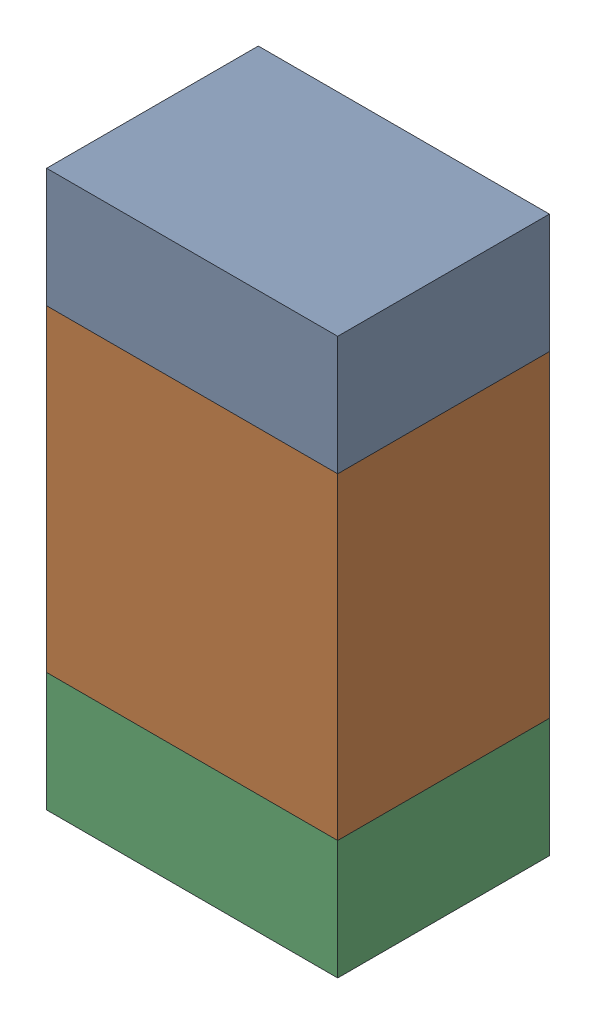
SolidWorks assembly R111_2PCB, configuration Default. Lengths in mm.
Overall size (0.55 1.05 0.4).
6 component instances, 2 part files, 0 mates.
Components (placement in the parent):
- 846483288-1: 846483288 [Default] at (115.7001 92.4124 0) size (0.55 0.22 0.4)
  - Extruded_12-1: Extruded_12 [Default] at origin size (0.55 0.22 0.4)
- 846483424-1: 846483424 [Default] at (115.7001 91.9999 0) size (0.55 0.6 0.4)
  - Extruded_13-1: Extruded_13 [Default] at origin size (0.55 0.6 0.4)
- 846483288-2: 846483288 [Default] at (115.7001 91.5874 0) size (0.55 0.22 0.4)
  - Extruded_12-1: Extruded_12 [Default] at origin size (0.55 0.22 0.4)
